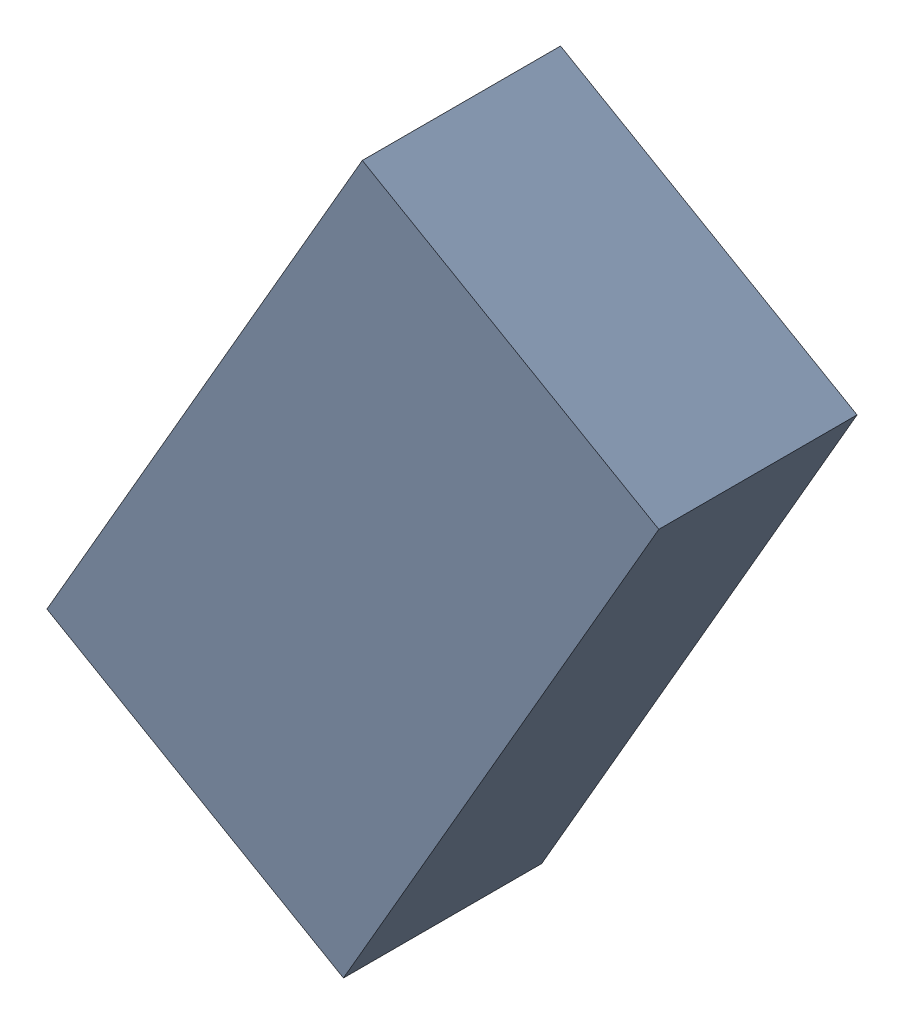
SolidWorks assembly L1_TDA3, configuration Standard. Lengths in mm.
Overall size (1.7 1.99 0.55).
2 component instances, 1 part files, 0 mates.
Components (placement in the parent):
- 885543600-1: 885543600 [Standard] at (46.7851 -30.8571 0) size (1.7 1.99 0.55)
  - Extruded_17-1: Extruded_17 [Standard] at origin size (1.7 1.99 0.55)
